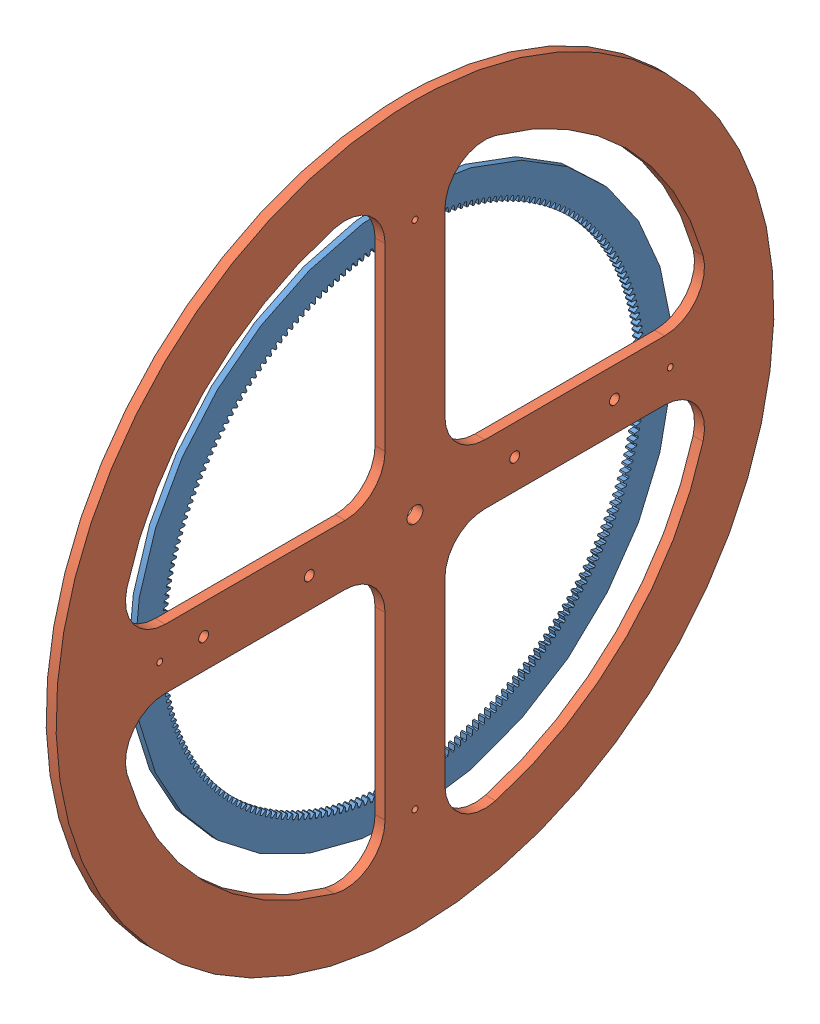
SolidWorks assembly Assem_Z1, configuration Default. Lengths in mm.
Overall size (9 360 360).
2 component instances, 2 part files, 3 mates.
Components (placement in the parent):
- Z1-1: Z1 [DIN - Internal spur gear 1M 240T 20PA 3FW ---S240S270OD 1.0AF] at (-67.5981 0.7513 34.3687) size (3 270 270)
- Centralno kolo-1: Centralno kolo [Default] at (-58.5981 0.7513 34.3687) x (0 1 0) z (-1 0 0) size (360 360 5)
Mates (geometry in assembly coordinates):
- Coincident1: coincident anti-aligned: axis of Z1-1 through (-64.5981 0.7513 34.3687) axis (-1 0 0); axis of Centralno kolo-1 through (-63.5981 0.7513 34.3687) axis (1 0 0)
- Coincident2: coincident anti-aligned: axis of Z1-1 through (-67.5981 -127.2487 34.3687) axis (1 0 0); axis of Centralno kolo-1 through (-58.5981 -127.2487 34.3687) axis (-1 0 0)
- Distance1: distance = 1 mm anti-aligned: plane of Centralno kolo-1 through (-63.5981 0.7513 34.3687) normal (-1 0 0); plane of Z1-1 through (-64.5981 0.7513 -84.6313) normal (1 0 0)
